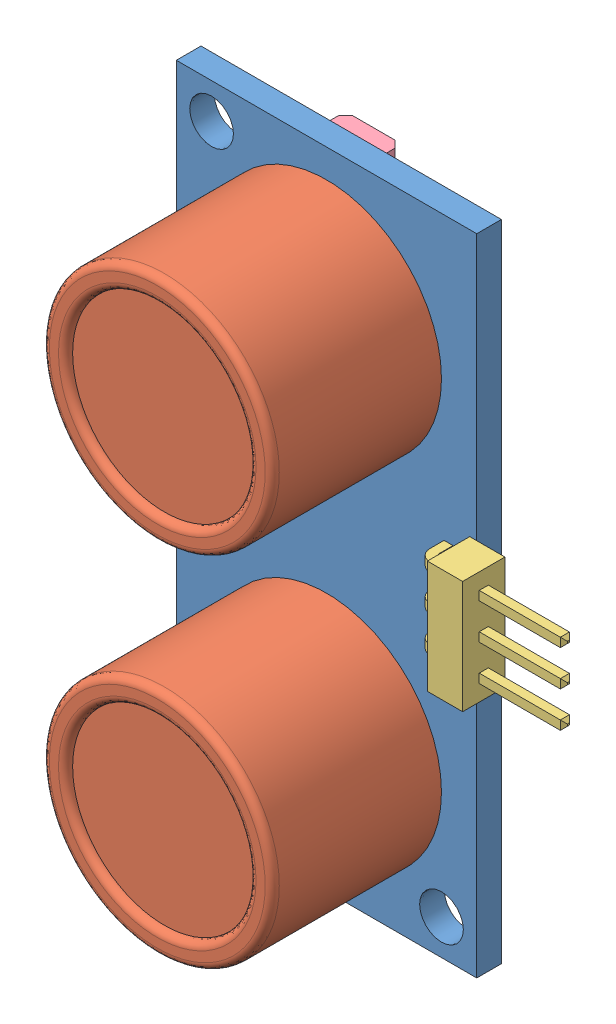
SolidWorks assembly Parallax Ping Sensor, configuration Default. Lengths in mm.
Overall size (29.3 45.7 15.59).
13 component instances, 5 part files, 42 mates.
Components (placement in the parent):
- Parallax Ping PCB-1: Parallax Ping PCB [Default] at origin size (21.3 45.7 1.75)
- Parallax Ping Transducer-1: Parallax Ping Transducer [Default] at (0 -12.69 13.25) x (1 0 0) z (0 -1 0) size (16.3 12 16.3)
- Parallax Ping Transducer-2: Parallax Ping Transducer [Default] at (0 12.69 13.25) x (1 0 0) z (0 -1 0) size (16.3 12 16.3)
- 3 Pin Header 90 Degree-1: 3 Pin Header 90 Degree [Default] at (11.4 0 3.25) x (0 0 1) z (0 -1 0) size (5.5 10.32 8)
- 14 Pin SMT-1: 14 Pin SMT [Default] at (0 -17.87 -0.85) x (1 0 0) z (0 1 0) size (6 1.6 8.8)
- 14 Pin SMT-2: 14 Pin SMT [Default] at (0 0.04 -0.85) x (1 0 0) z (0 1 0) size (6 1.6 8.8)
- 14 Pin SMT-3: 14 Pin SMT [Default] at (0 17.95 -0.85) x (1 0 0) z (0 1 0) size (6 1.6 8.8)
- Cap1 SMT-1: Cap1 SMT [Default] at (-2.155 7.9 -0.9689) x (0 1 0) z (-1 0 0) size (4.5 1.84 1.75)
- Cap1 SMT-2: Cap1 SMT [Default] at (7.235 7.9 -0.9689) x (0 1 0) z (-1 0 0) size (4.5 1.84 1.75)
- Cap1 SMT-3: Cap1 SMT [Default] at (-7.235 7.9 -0.9689) x (0 1 0) z (-1 0 0) size (4.5 1.84 1.75)
- Cap1 SMT-4: Cap1 SMT [Default] at (4.695 7.9 -0.9689) x (0 1 0) z (-1 0 0) size (4.5 1.84 1.75)
- Cap1 SMT-5: Cap1 SMT [Default] at (2.155 7.9 -0.9689) x (0 1 0) z (-1 0 0) size (4.5 1.84 1.75)
- Cap1 SMT-6: Cap1 SMT [Default] at (-4.695 7.9 -0.9689) x (0 1 0) z (-1 0 0) size (4.5 1.84 1.75)
Mates (geometry in assembly coordinates):
- Coincident1: coincident anti-aligned: plane of Parallax Ping PCB-1 through (-10.65 -22.85 1.75) normal (0 0 1); plane of Parallax Ping Transducer-2 through (0 12.69 1.75) normal (0 0 -1)
- Coincident2: coincident anti-aligned: plane of Parallax Ping PCB-1 through (-10.65 -22.85 1.75) normal (0 0 1); plane of Parallax Ping Transducer-1 through (0 -12.69 1.75) normal (0 0 -1)
- Coincident3: coincident aligned: plane of Parallax Ping PCB-1; plane of Parallax Ping Transducer-1
- Coincident4: coincident aligned: plane of Parallax Ping PCB-1; plane of Parallax Ping Transducer-2
- Distance2: distance = 10.16 mm: plane of Parallax Ping PCB-1 through (-10.65 -22.85 1.75) normal (0 -1 0); point of Parallax Ping Transducer-1
- Distance3: distance = 10.16 mm: plane of Parallax Ping PCB-1 through (-10.65 22.85 1.75) normal (0 1 0); point of Parallax Ping Transducer-2
- Coincident7: coincident anti-aligned: plane of Parallax Ping PCB-1 through (-10.65 -22.85 1.75) normal (0 0 1); plane of 3 Pin Header 90 Degree-1 through (10.15 -4 1.75) normal (0 0 -1)
- Coincident8: coincident anti-aligned: plane of Parallax Ping PCB-1; plane of 3 Pin Header 90 Degree-1
- Coincident9: coincident anti-aligned: plane of Parallax Ping PCB-1 through (-10.65 -22.85 0) normal (0 0 -1); plane of 14 Pin SMT-1 through (3 -18.12 0) normal (0 0 1)
- Coincident10: coincident anti-aligned: plane of Parallax Ping PCB-1 through (-10.65 -22.85 0) normal (0 0 -1); plane of 14 Pin SMT-2 through (3 -0.21 0) normal (0 0 1)
- Coincident11: coincident anti-aligned: plane of Parallax Ping PCB-1 through (-10.65 -22.85 0) normal (0 0 -1); plane of 14 Pin SMT-3 through (3 18.95 0) normal (0 0 1)
- Coincident12: coincident aligned: plane of Parallax Ping PCB-1; plane of 14 Pin SMT-1
- Coincident13: coincident aligned: plane of Parallax Ping PCB-1; plane of 14 Pin SMT-2
- Coincident14: coincident aligned: plane of Parallax Ping PCB-1; plane of 14 Pin SMT-3
- Distance4: distance = 0.58 mm aligned: plane of Parallax Ping PCB-1 through (-10.65 -22.85 1.75) normal (0 -1 0); plane of 14 Pin SMT-1 through (-2 -22.27 -1.6) normal (0 -1 0)
- Distance5: distance = 9.11 mm anti-aligned: plane of 14 Pin SMT-1 through (-2 -13.47 -1.6) normal (0 1 0); plane of 14 Pin SMT-2 through (-2 -4.36 -1.6) normal (0 -1 0)
- Distance6: distance = 9.11 mm anti-aligned: plane of 14 Pin SMT-2 through (-2 4.44 -1.6) normal (0 1 0); plane of 14 Pin SMT-3 through (-2 13.55 -1.6) normal (0 -1 0)
- Coincident15: coincident anti-aligned: plane of Parallax Ping PCB-1 through (-10.65 -22.85 0) normal (0 0 -1); plane of Cap1 SMT-1 through (-2.405 10.15 0) normal (0 0 1)
- Coincident16: coincident anti-aligned: plane of Parallax Ping PCB-1 through (-10.65 -22.85 0) normal (0 0 -1); plane of Cap1 SMT-2 through (6.985 10.15 0) normal (0 0 1)
- Coincident17: coincident anti-aligned: plane of Parallax Ping PCB-1 through (-10.65 -22.85 0) normal (0 0 -1); plane of Cap1 SMT-3 through (-7.485 10.15 0) normal (0 0 1)
- Coincident18: coincident anti-aligned: plane of Parallax Ping PCB-1 through (-10.65 -22.85 0) normal (0 0 -1); plane of Cap1 SMT-4 through (4.445 10.15 0) normal (0 0 1)
- Coincident19: coincident anti-aligned: plane of Parallax Ping PCB-1 through (-10.65 -22.85 0) normal (0 0 -1); plane of Cap1 SMT-5 through (1.905 10.15 0) normal (0 0 1)
- Coincident20: coincident anti-aligned: plane of Parallax Ping PCB-1 through (-10.65 -22.85 0) normal (0 0 -1); plane of Cap1 SMT-6 through (-4.945 10.15 0) normal (0 0 1)
- Parallel1: parallel aligned: plane of Cap1 SMT-4 through (3.82 6.15 -1.8439) normal (0 -1 0); plane of Cap1 SMT-5 through (1.28 6.15 -1.8439) normal (0 -1 0)
- Parallel2: parallel aligned: plane of Cap1 SMT-2 through (6.36 6.15 -1.8439) normal (0 -1 0); plane of Cap1 SMT-4 through (3.82 6.15 -1.8439) normal (0 -1 0)
- Parallel3: parallel aligned: plane of Parallax Ping PCB-1 through (-10.65 -22.85 1.75) normal (0 -1 0); plane of Cap1 SMT-2 through (6.36 6.15 -1.8439) normal (0 -1 0)
- Distance7: distance = 0.79 mm anti-aligned: plane of Cap1 SMT-2 through (6.36 6.15 -1.8439) normal (-1 0 0); plane of Cap1 SMT-4 through (5.57 6.15 -1.8439) normal (1 0 0)
- Distance8: distance = 0.79 mm anti-aligned: plane of Cap1 SMT-4 through (3.82 6.15 -1.8439) normal (-1 0 0); plane of Cap1 SMT-5 through (3.03 6.15 -1.8439) normal (1 0 0)
- Distance9: distance = 2.54 mm aligned: plane of Parallax Ping PCB-1 through (10.65 22.85 1.75) normal (1 0 0); plane of Cap1 SMT-2 through (8.11 6.15 -1.8439) normal (1 0 0)
- Coincident21: coincident aligned: plane of Cap1 SMT-4 through (3.82 9.65 -0.0939) normal (0 1 0); plane of Cap1 SMT-5 through (1.28 9.65 -0.0939) normal (0 1 0)
- Coincident22: coincident aligned: plane of Cap1 SMT-2 through (6.36 9.65 -0.0939) normal (0 1 0); plane of Cap1 SMT-4 through (3.82 9.65 -0.0939) normal (0 1 0)
- Parallel4: parallel aligned: plane of Cap1 SMT-3 through (-8.11 6.15 -1.8439) normal (0 -1 0); plane of Cap1 SMT-6 through (-5.57 6.15 -1.8439) normal (0 -1 0)
- Parallel5: parallel aligned: plane of Cap1 SMT-1 through (-3.03 6.15 -1.8439) normal (0 -1 0); plane of Cap1 SMT-6 through (-5.57 6.15 -1.8439) normal (0 -1 0)
- Distance11: distance = 0.79 mm anti-aligned: plane of Cap1 SMT-1 through (-3.03 6.15 -1.8439) normal (-1 0 0); plane of Cap1 SMT-6 through (-3.82 6.15 -1.8439) normal (1 0 0)
- Distance12: distance = 0.79 mm anti-aligned: plane of Cap1 SMT-3 through (-6.36 6.15 -1.8439) normal (1 0 0); plane of Cap1 SMT-6 through (-5.57 6.15 -1.8439) normal (-1 0 0)
- Coincident23: coincident aligned: plane of Cap1 SMT-3 through (-8.11 9.65 -0.0939) normal (0 1 0); plane of Cap1 SMT-6 through (-5.57 9.65 -0.0939) normal (0 1 0)
- Coincident24: coincident aligned: plane of Cap1 SMT-1 through (-3.03 9.65 -0.0939) normal (0 1 0); plane of Cap1 SMT-6 through (-5.57 9.65 -0.0939) normal (0 1 0)
- Parallel6: parallel aligned: plane of Parallax Ping PCB-1 through (-10.65 -22.85 1.75) normal (0 -1 0); plane of Cap1 SMT-3 through (-8.11 6.15 -1.8439) normal (0 -1 0)
- Distance13: distance = 2.54 mm aligned: plane of Parallax Ping PCB-1 through (-10.65 22.85 1.75) normal (-1 0 0); plane of Cap1 SMT-3 through (-8.11 6.15 -1.8439) normal (-1 0 0)
- Coincident25: coincident aligned: plane of Cap1 SMT-1 through (-3.03 9.65 -0.0939) normal (0 1 0); plane of Cap1 SMT-5 through (1.28 9.65 -0.0939) normal (0 1 0)
- Distance14: distance = 2 mm aligned: plane of Parallax Ping PCB-1 through (10.65 22.85 1.75) normal (1 0 0); plane of 3 Pin Header 90 Degree-1 through (12.65 -4 1.75) normal (1 0 0)
- Distance15: distance = 1.71 mm anti-aligned: plane of 14 Pin SMT-2 through (-2 4.44 -1.6) normal (0 1 0); plane of Cap1 SMT-5 through (1.28 6.15 -1.8439) normal (0 -1 0)
